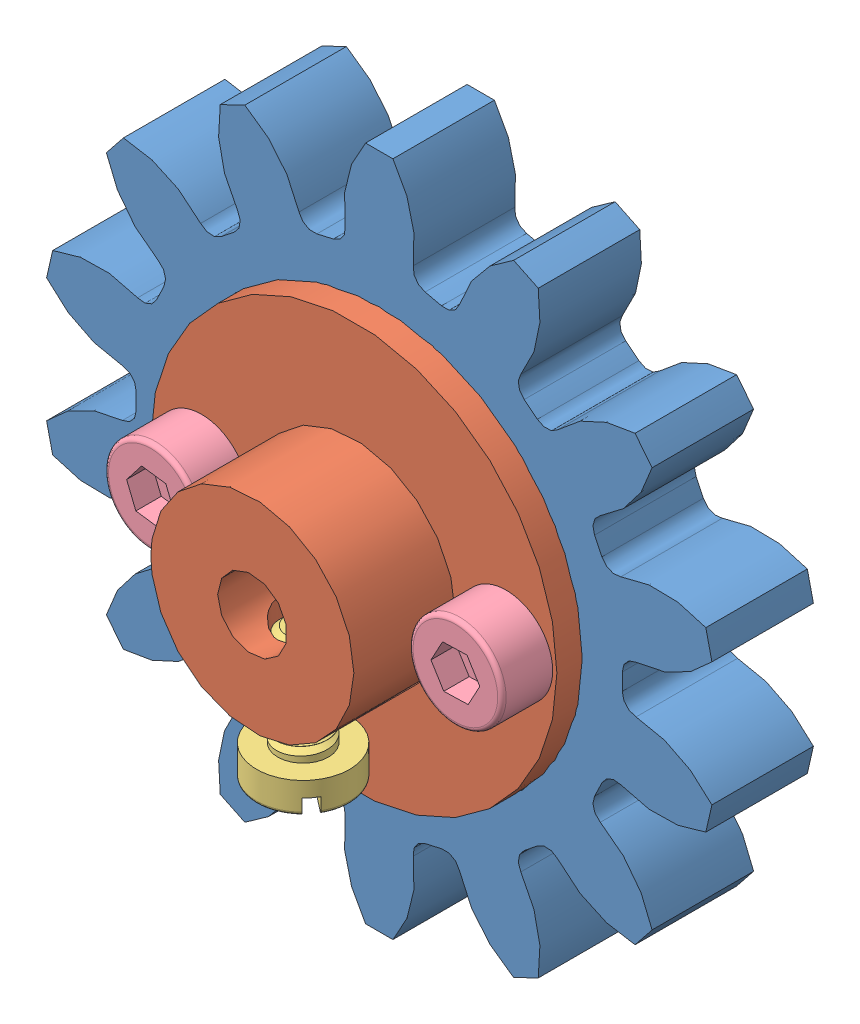
SolidWorks assembly engrenage-complet, configuration Défaut. Lengths in mm.
Overall size (39.32 40 14.86).
7 component instances, 5 part files, 15 mates.
Components (placement in the parent):
- engrenage-1: engrenage [Défaut] at (1.0609 0.1936 0) size (39.32 40 6)
- engrenage-bague_arret-1: engrenage-bague_arret [Défaut] at (-0.3178 -0.3667 13.5) x (-1 0 0) z (0 0 -1) size (24 24 8)
- vis-tc-m3x6-1: vis-tc-m3x6 [Défaut] at (-0.3178 -8.4167 10.5) x (-0.611546 0 0.791209) z (0.791209 0 0.611546) size (5.5 7.83 5.5)
- vis-chc-1: vis-chc [Vis CHC M3x8] at (-9.3178 -0.3667 7.5) x (0.40091 -0.916118 0) z (-0.916118 -0.40091 0) size (5.5 11 5.5)
- vis-chc-2: vis-chc [Vis CHC M3x8] at (8.6822 -0.3667 7.5) x (0.998484 0.055044 0) z (0.055044 -0.998484 0) size (5.5 11 5.5)
- ecrou-h-1: ecrou-h [6012 HU M3] at (8.6822 -0.3667 -0.4) x (1 0 0) z (0 1 0) size (5.5 2.4 6.35)
- ecrou-h-2: ecrou-h [6012 HU M3] at (-9.3178 -0.3667 -0.4) x (1 0 0) z (0 1 0) size (5.5 2.4 6.35)
Mates (geometry in assembly coordinates):
- Coïncidente1: coincident anti-aligned: line of 14 dents module 2.5 axe D4-1 through (-9.3178 -0.3667 2) axis (0 0 1); line of Bague d'arrêt 4x12x24-1 through (-9.3178 -0.3667 7.5) axis (0 0 -1)
- Coïncidente2: coincident anti-aligned: line of 14 dents module 2.5 axe D4-1 through (8.6822 -0.3667 2) axis (0 0 1); line of Bague d'arrêt 4x12x24-1 through (8.6822 -0.3667 7.5) axis (0 0 -1)
- Coïncidente3: coincident anti-aligned: plane of 14 dents module 2.5 axe D4-1 through (-0.3178 -0.3667 5.5) normal (0 0 1); plane of Bague d'arrêt 4x12x24-1 through (-0.3178 -0.3667 5.5) normal (0 0 -1)
- Coïncidente8: coincident anti-aligned: line of Bague d'arrêt 4x12x24-1 through (-0.3178 -6.3667 10.5) axis (0 1 0); line of Vis TC M3X6-1 through (-0.3178 -2.9167 10.5) axis (0 -1 0)
- Tangent1: tangent anti-aligned: cylinder of Bague d'arrêt 4x12x24-1 through (-0.3178 -0.3667 13.5) axis (0 0 -1) radius 2.05; plane of Vis TC M3X6-1 through (-0.3178 -2.4167 10.5) normal (0 1 0)
- Coaxiale1: concentric anti-aligned: cylinder of engrenage-bague_arret-1 through (8.6822 -0.3667 13.5) axis (0 0 -1) radius 1.55; cylinder of vis-chc-2 through (8.6822 -0.3667 -0.5) axis (0 0 1) radius 1.5
- Coaxiale2: concentric anti-aligned: cylinder of engrenage-bague_arret-1 through (-9.3178 -0.3667 13.5) axis (0 0 -1) radius 1.55; cylinder of vis-chc-1 through (-9.3178 -0.3667 -0.5) axis (0 0 1) radius 1.5
- Coïncidente9: coincident anti-aligned: plane of engrenage-bague_arret-1 through (-0.3178 -0.3667 7.5) normal (0 0 1); plane of vis-chc-2 through (8.6822 -0.3667 7.5) normal (0 0 -1)
- Coïncidente10: coincident anti-aligned: plane of engrenage-bague_arret-1 through (-0.3178 -0.3667 7.5) normal (0 0 1); plane of vis-chc-1 through (-9.3178 -0.3667 7.5) normal (0 0 -1)
- Coaxiale3: concentric anti-aligned: cylinder of vis-chc-2 through (8.6822 -0.3667 -0.5) axis (0 0 1) radius 1.5; cylinder of ecrou-h-1 through (8.6822 -0.3667 -3.102) axis (0 0 -1) radius 1.2295
- Parallèle1: parallel: line of engrenage-1 through (3.2 5.9109 1.2333) axis (0 0.866025 0.5); plane of ecrou-h-1 through (5.9322 1.221 -3.102) normal (-0.5 0.866025 0)
- Coaxiale4: concentric anti-aligned: cylinder of vis-chc-1 through (-9.3178 -0.3667 -0.5) axis (0 0 1) radius 1.5; cylinder of ecrou-h-2 through (-9.3178 -0.3667 2) axis (0 0 -1) radius 1.2295
- Parallèle2: parallel anti-aligned: plane of engrenage-1 through (-12.0891 1.2333 2) normal (0.5 -0.866025 0); plane of ecrou-h-2 through (-12.0678 1.221 2) normal (-0.5 0.866025 0)
- Coïncidente13: coincident anti-aligned: plane of engrenage-1 through (1.0609 0.1936 2) normal (0 0 -1); plane of ecrou-h-2 through (-6.5678 -1.9544 2) normal (0 0 1)
- Coïncidente14: coincident anti-aligned: plane of engrenage-1 through (1.0609 0.1936 2) normal (0 0 -1); plane of ecrou-h-1 through (11.4322 -1.9544 2) normal (0 0 1)
